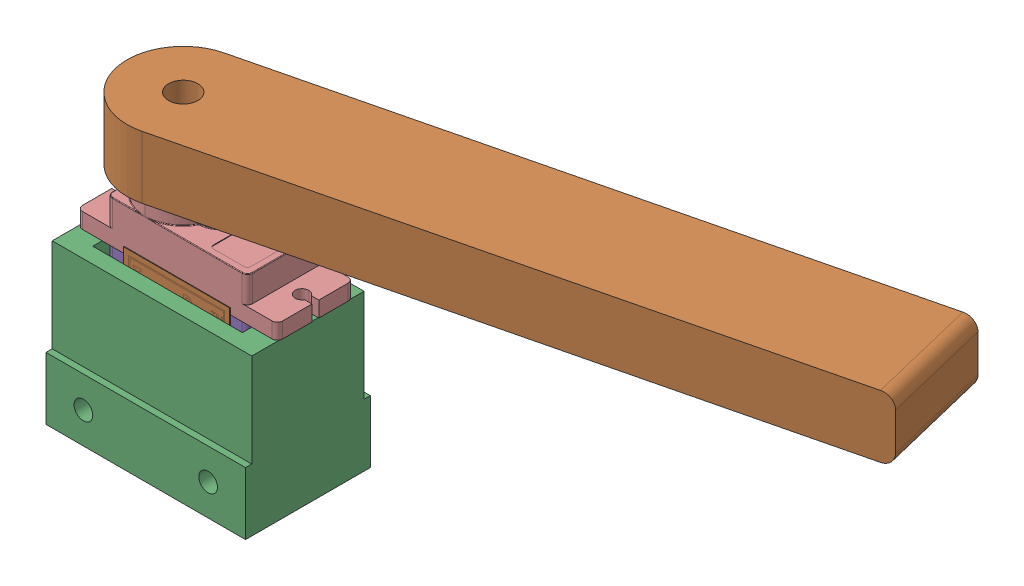
SolidWorks assembly Assemblage_Pic_Panneau_Solaire, configuration Défaut. Lengths in mm.
Overall size (110.88 46.75 43.32).
3 component instances, 3 part files, 5 mates.
Components (placement in the parent):
- Servo_SG90-1: Servo_SG90 [Défaut] at (-12.8661 -23.9295 0) size (32.1 29.95 12.4)
- Bras_Panneau_Solaire-1: Bras_Panneau_Solaire [Défaut] at (-11.3428 9.0882 27.7832) x (0.971503 0 -0.237028) z (0 1 0) size (109 18 10)
- Support_Servo-1: Support_Servo [Défaut] at (-6.9428 -27.6618 28.1832) x (1 0 0) z (0 1 0) size (32 20 25)
Mates (geometry in assembly coordinates):
- Coaxiale1: concentric anti-aligned: circle of Servo_SG90-1; cylinder of bras_panneau_solaire-1 through (-11.3428 19.0882 27.7832) axis (0 -1 0) radius 2.35
- Coïncidente1: coincident anti-aligned: plane of Servo_SG90-1 through (-11.3428 9.0882 27.7832) normal (0 1 0); plane of bras_panneau_solaire-1 through (-11.3428 9.0882 27.7832) normal (0 -1 0)
- Coïncidente2: coincident anti-aligned: plane of Servo_SG90-1 through (-16.5928 -17.6618 33.0332) normal (0 -1 0); plane of Support Servo-1 through (-6.9428 -17.6618 28.1832) normal (0 1 0)
- Coïncidente3: coincident anti-aligned: plane of Servo_SG90-1 through (-16.5928 -1.9618 21.6832) normal (0 0 -1); plane of Support Servo-1 through (-18.9428 -2.6618 21.6832) normal (0 0 1)
- Coïncidente5: coincident anti-aligned: plane of Servo_SG90-1 through (5.0572 -1.9618 33.0332) normal (1 0 0); plane of Support Servo-1 through (5.0572 -2.6618 21.6832) normal (-1 0 0)
